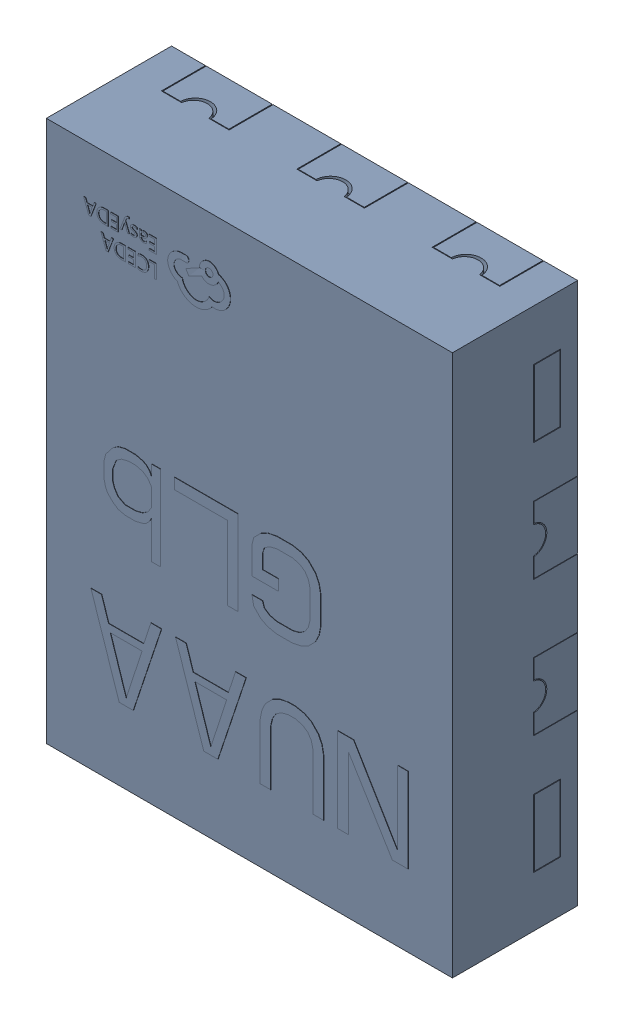
SolidWorks assembly U9, configuration Défaut. Lengths in mm.
Overall size (1.2 1.6 0.38).
4 component instances, 1 part files, 0 mates.
Components (placement in the parent):
- FUSB301TMX-1: FUSB301TMX [Défaut] at (72.2617 -16.2077 -1.6) x (0 -1 0) z (0 0 1) size (1.6 1.2 0.38)
  - U1.step_988-1: U1.step_988 [Défaut] at (5.0775 -6.7805 1.6001) size (1.6 1.2 0.38)
    - TMLP-10_L1.6-W1.2-P0.40.step-1: TMLP-10_L1.6-W1.2-P0.40.step [Défaut] at origin size (1.6 1.2 0.38)
      - SOLID.step_990-1: SOLID.step_990 [Défaut] at origin size (1.6 1.2 0.38)
